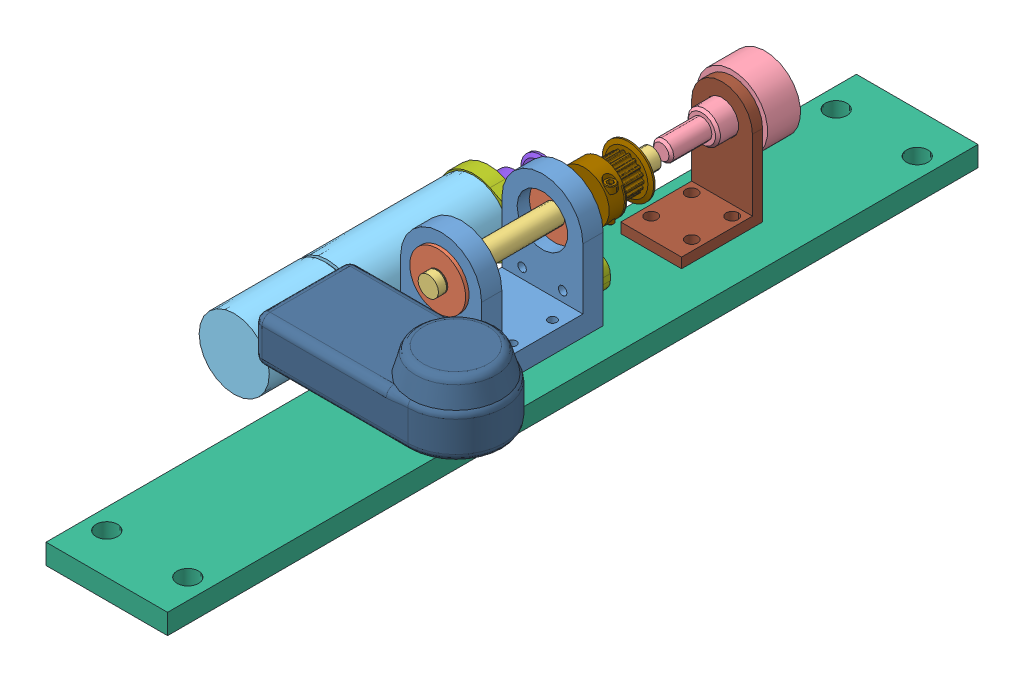
SolidWorks assembly NECK_YOKE_ASM, configuration Default. Lengths in mm.
Overall size (86.8 44.45 254).
12 component instances, 11 part files, 28 mates.
Components (placement in the parent):
- n01-yoke-2: n01-yoke [Default] at origin size (28.53 38.1 38.1)
- 000_rb-p25xp625-57155K324mcm-1: 000_rb-p25xp625-57155K324mcm [Default] at (0 25.4 -16.51) x (0 0 1) z (-0.947787 -0.318905 0) size (3.61 17.53 17.53)
- 000_rb-p25xp625-57155K324mcm-2: 000_rb-p25xp625-57155K324mcm [Default] at (0 25.4 16.51) x (0 0 -1) z (0.870377 -0.492386 0) size (3.61 17.53 17.53)
- n02-neck-pitch-shaft-1: n02-neck-pitch-shaft [Default] at (0 25.4 -11.8618) x (0.984383 -0.176038 0) z (0 0 1) size (6.34 6.34 69.85)
- bourns-6639-1: bourns-6639 [Default] at (0 25.4 -82.4992) x (0 0 -1) z (0.999946 -0.010393 0) size (35.71 22.23 22.23)
- MAXON-amax22-n-gear143991-1: MAXON-amax22-n-gear143991 [Default] at (-27.94 9.525 26.75) x (0 0 1) z (-1 0 0) size (89.5 22 22)
- n03-neck-baseplate-to-body-1: n03-neck-baseplate-to-body [Default] at (3.175 0 0) x (0 0 -1) z (0 -1 0) size (254 38.1 6.35)
- n04-motor-mount-1: n04-motor-mount [Default] at (-27.94 9.525 -19.05) x (-1 0 0) z (0 0 -1) size (49.53 22.86 4.76)
- a_6d16m012df6003-3mm-bored-to-4mm-1: a_6d16m012df6003-3mm-bored-to-4mm [Default] at (-27.94 9.525 -32.3525) size (12.2 12.2 14.3)
- a_6d16-018df2508-2: a_6d16-018df2508 [Default] at (0 25.4 -31.6681) x (0.999994 -0.003333 0) z (0 0 1) size (16.13 16.13 14.29)
- LOGITECH_USB_CAM-1: LOGITECH_USB_CAM [Default] at (32.385 15.875 46.7995) x (0 0 -1) z (0 1 0) size (30.1 63.31 29.21)
- n11-neck-pot-holder-2: n11-neck-pot-holder [Default] at (0 0 -59.4868) size (25.35 34.92 25.4)
Mates (geometry in assembly coordinates):
- Coincident1: coincident anti-aligned: plane of n01-yoke-2 through (0 25.4 -19.05) normal (0 0 -1); plane of 000_rb-p25xp625-57155K324mcm-1 through (8.3055 28.1946 -19.05) normal (0 0 1)
- Coincident2: coincident anti-aligned: plane of n01-yoke-2 through (0 25.4 19.05) normal (0 0 1); plane of 000_rb-p25xp625-57155K324mcm-2 through (-7.6271 29.7148 19.05) normal (0 0 -1)
- Concentric1: concentric aligned: cylinder of n01-yoke-2; cylinder of 000_rb-p25xp625-57155K324mcm-2
- Concentric2: concentric anti-aligned: cylinder of n01-yoke-2; cylinder of 000_rb-p25xp625-57155K324mcm-1
- Concentric3: concentric anti-aligned: cylinder of 000_rb-p25xp625-57155K324mcm-1; cylinder of n02-neck-pitch-shaft-1
- Concentric4: concentric aligned: cylinder of n02-neck-pitch-shaft-1; cylinder of bourns-6639-1
- Coincident6: coincident anti-aligned: plane of n01-yoke-2 through (12.7 0 19.05) normal (0 -1 0); plane of n03-neck-baseplate-to-body-1 through (-15.875 0 127) normal (0 1 0)
- Coincident7: coincident anti-aligned: plane of n01-yoke-2 through (0 0 0) normal (0 0 1); plane of n03-neck-baseplate-to-body-1 through (3.175 0 0) normal (0 0 -1)
- Coincident8: coincident anti-aligned: plane of n01-yoke-2 through (0 0 0) normal (0 1 0); plane of n03-neck-baseplate-to-body-1 through (3.175 0 0) normal (0 -1 0)
- Coincident11: coincident aligned: plane of MAXON-amax22-n-gear143991-1 through (-22.94 9.525 -19.05) normal (0 0 -1); plane of n01-yoke-2 through (0 25.4 -19.05) normal (0 0 -1)
- Concentric6: concentric aligned: cylinder of MAXON-amax22-n-gear143991-1; cylinder of n04-motor-mount-1
- Concentric7: concentric aligned: cylinder of MAXON-amax22-n-gear143991-1; cylinder of n04-motor-mount-1
- Coincident12: coincident anti-aligned: plane of MAXON-amax22-n-gear143991-1 through (-22.94 9.525 -19.05) normal (0 0 -1); plane of n04-motor-mount-1 through (-27.94 9.525 -19.05) normal (0 0 1)
- Parallel2: parallel aligned: plane of n03-neck-baseplate-to-body-1 through (-15.875 0 127) normal (0 1 0); plane of n04-motor-mount-1 through (-12.065 14.2875 -23.8125) normal (0 1 0)
- Concentric8: concentric aligned: cylinder of n01-yoke-2; cylinder of n04-motor-mount-1
- Concentric9: concentric anti-aligned: cylinder of n01-yoke-2; cylinder of n03-neck-baseplate-to-body-1
- Coincident15: coincident aligned: plane of 000_rb-p25xp625-57155K324mcm-1 through (3.0092 26.4125 -20.1168) normal (0 0 -1); plane of n02-neck-pitch-shaft-1 through (29.287 20.1626 -20.1168) normal (0 0 -1)
- Distance3: distance = 3.175 mm anti-aligned: plane of n02-neck-pitch-shaft-1 through (0 25.4 -46.7868) normal (0 0 -1); plane of bourns-6639-1 through (0.033 28.5748 -49.9618) normal (0 0 1)
- Concentric10: concentric anti-aligned: cylinder of n02-neck-pitch-shaft-1; cylinder of a_6d16-018df2508-2
- Distance4: distance = 2.54 mm anti-aligned: plane of n04-motor-mount-1 through (-27.94 9.525 -23.8125) normal (0 0 -1); plane of a_6d16m012df6003-3mm-bored-to-4mm-1 through (-27.94 15.625 -26.3525) normal (0 0 1)
- Concentric12: concentric aligned: cylinder of MAXON-amax22-n-gear143991-1; cylinder of a_6d16m012df6003-3mm-bored-to-4mm-1
- Coincident19: coincident aligned: plane of a_6d16m012df6003-3mm-bored-to-4mm-1 through (-27.94 14.4992 -40.0025) normal (0 0 -1); plane of a_6d16-018df2508-2 through (0 25.4 -40.0025) normal (0 0 -1)
- Coincident20: coincident aligned: plane of n03-neck-baseplate-to-body-1 through (-15.875 -6.35 127) normal (-1 0 0); plane of LOGITECH_USB_CAM-1 through (-15.875 29.845 61.849) normal (-1 0 0)
- Distance5: distance = 12.7 mm anti-aligned: plane of n01-yoke-2 through (0 25.4 19.05) normal (0 0 1); plane of LOGITECH_USB_CAM-1 through (32.385 29.845 31.75) normal (0 0 -1)
- Distance6: distance = 15.875 mm anti-aligned: plane of n03-neck-baseplate-to-body-1 through (-15.875 0 127) normal (0 1 0); plane of LOGITECH_USB_CAM-1 through (32.385 15.875 46.7995) normal (0 -1 0)
- Coincident21: coincident anti-aligned: plane of n03-neck-baseplate-to-body-1 through (-15.875 0 127) normal (0 1 0); plane of n11-neck-pot-holder-2 through (9.525 0 -46.7868) normal (0 -1 0)
- Coincident22: coincident anti-aligned: plane of bourns-6639-1 through (0.1155 36.5119 -72.1868) normal (0 0 1); plane of n11-neck-pot-holder-2 through (0 25.4 -72.1868) normal (0 0 -1)
- Concentric13: concentric aligned: cylinder of bourns-6639-1; cylinder of n11-neck-pot-holder-2
